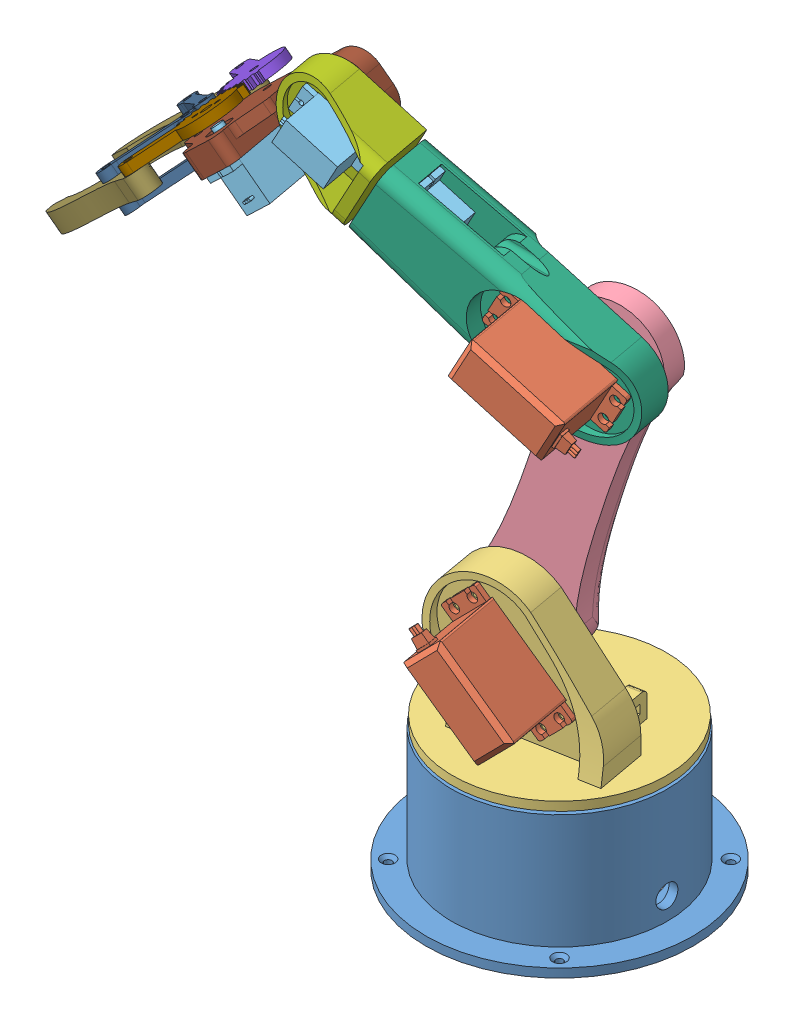
SolidWorks assembly Robotic Arm, configuration Default. Lengths in mm.
Overall size (257.43 292.37 143.8).
21 component instances, 12 part files, 26 mates.
Components (placement in the parent):
- Base-1: Base [Default] at (40.7793 36.1076 92.8796) size (121.25 56 121.25)
- Servo Motor MG996R-1: Servo Motor MG996R [Default] at (30.5293 45.3076 92.8796) x (-1 0 0) z (0 0 -1) size (55.8 47.4 21)
- Waist-1: Waist [Default] at (40.7793 93.1076 92.8796) x (-0.178802 0 -0.983885) z (0.983885 0 -0.178802) size (97 64.78 97)
- Servo Motor MG996R-2: Servo Motor MG996R [Default] at (43.1871 126.313 142.4478) x (0.695712 -0.707107 -0.126432) z (0.695712 0.707107 -0.126432) size (55.8 47.4 21)
- Arm 01-1: Arm 01 [Default] at (27.5808 133.5608 97.1076) x (-0.941109 0.291655 0.171029) z (-0.178802 0 -0.983885) size (54.87 166.68 26.36)
- Servo Motor Micro  9g-1: Servo Motor Micro  9g [Default] at (9.904 276.4834 111.1953) x (0.448013 0.890312 -0.081418) z (0.178802 0 0.983885) size (32.6 29.9 12.4)
- Servo Motor MG996R-7: Servo Motor MG996R [Default] at (61.512 253.011 139.1176) x (-0.875965 0.455351 0.15919) z (-0.448013 -0.890312 0.081418) size (55.8 47.4 21)
- Arm 02 v3-1: Arm 02 v3 [Default] at (32.6174 264.3897 101.4775) x (0.448013 0.890312 -0.081418) z (0.178802 0 0.983885) size (38.57 115 28.32)
- Arm 03-1: Arm 03 [Default] at (-16.3245 290.0092 116.0058) x (0.449545 0.890278 -0.072895) z (0.174916 -0.00771 0.984553) size (33 46 28)
- Servo Motor Micro  9g-2: Servo Motor Micro  9g [Default] at (-33.8391 300.3245 133.9765) x (0.875965 -0.455351 -0.15919) z (0.449545 0.890278 -0.072895) size (32.6 29.9 12.4)
- Gripper Assembly-1: Gripper Assembly [Default] at (-33.1508 318.0568 111.777) x (0.174916 -0.00771 0.984553) z (-0.719312 -0.683812 0.122438) size (98.22 36.05 139.41)
  - gear1-1: gear1 [Default] at (-22.9056 12.6028 63.2843) x (-0.581668 0 0.813426) z (-0.813426 0 -0.581668) size (49.29 4 26.63)
  - gear2-1: gear2 [Default] at (5.149 12.6028 46.1292) x (-0.467421 0 -0.884035) z (0.884035 0 -0.467421) size (49.02 4 26.63)
  - grip link 1-1: grip link 1 [Default] at (-26.7426 0.1028 100.5029) x (0.571471 0 -0.820623) z (0.820623 0 0.571471) size (39 4 8)
  - Gripper base-1: Gripper base [Default] at (-22.027 4.1028 80.0636) size (44.4 28 77)
  - grip link 1-2: grip link 1 [Default] at (18.9346 0.1028 100.3298) x (-0.579406 0 -0.815039) z (0.815039 0 -0.579406) size (39 4 8)
  - Gripper 1-1: Gripper 1 [Default] at (25.0683 4.1028 73.5645) x (0 1 0) z (0.39713 0 -0.917762) size (8.5 22.22 65.31)
  - Gripper 1-2: Gripper 1 [Default] at (-32.1279 12.6028 73.5771) x (0 -1 0) z (-0.371396 0 -0.928475) size (8.5 22.22 65.31)
  - Servo Motor Micro  9g-1: Servo Motor Micro  9g [Default] at (4.773 -19.4472 55.0636) x (-1 0 0) z (0 0 -1) size (32.6 29.9 12.4)
  - grip link 1-3: grip link 1 [Default] at (18.9346 12.6028 100.3298) x (-0.579406 0 -0.815039) z (0.815039 0 -0.579406) size (39 4 8)
  - grip link 1-4: grip link 1 [Default] at (-26.7426 16.6028 100.5029) x (0.571471 0 -0.820623) z (-0.820623 0 -0.571471) size (39 4 8)
Mates (geometry in assembly coordinates):
- Coincident1: coincident anti-aligned: plane of Base-1 through (40.7793 74.1076 105.8796) normal (0 1 0); plane of Servo Motor MG996R-1 through (57.8293 74.1076 102.1296) normal (0 -1 0)
- Concentric1: concentric aligned: cylinder of Base-1 through (54.5293 66.9076 87.8796) axis (0 1 0) radius 1.3; cylinder of Servo Motor MG996R-1 through (54.5293 69.7076 87.8796) axis (0 1 0) radius 2.1
- Concentric4: concentric aligned: cylinder of Base-1 through (6.5293 66.9076 97.8796) axis (0 1 0) radius 1.3; cylinder of Servo Motor MG996R-1 through (6.5293 69.7076 97.8796) axis (0 1 0) radius 2.1
- Concentric5: concentric aligned: cylinder of Base-1 through (40.7793 92.1076 92.8796) axis (0 -1 0) radius 49; cylinder of Waist-1 through (40.7793 97.1076 92.8796) axis (0 -1 0) radius 48.5
- Distance1: distance = 1 mm anti-aligned: plane of Base-1 through (40.7793 92.1076 92.8796) normal (0 1 0); plane of Waist-1 through (40.7793 93.1076 92.8796) normal (0 -1 0)
- Coincident4: coincident anti-aligned: plane of Waist-1 through (43.9977 93.1076 110.5895) normal (0.178802 0 0.983885); plane of Servo Motor MG996R-2 through (12.1802 139.0763 116.3717) normal (-0.178802 0 -0.983885)
- Coincident5: coincident anti-aligned: plane of Waist-1 through (64.4552 119.0651 137.8723) normal (-0.695712 0.707107 0.126432); plane of Servo Motor MG996R-2 through (57.9645 119.0651 102.1563) normal (0.695712 -0.707107 -0.126432)
- Coincident6: coincident anti-aligned: plane of Waist-1 through (64.4552 119.0651 137.8723) normal (-0.695712 -0.707107 0.126432); plane of Servo Motor MG996R-2 through (29.4404 148.0565 107.34) normal (0.695712 0.707107 -0.126432)
- Coincident7: coincident anti-aligned: plane of Servo Motor MG996R-2 through (27.5808 133.5608 97.1076) normal (-0.178802 0 -0.983885); plane of Arm 01-1 through (27.5808 133.5608 97.1076) normal (0.178802 0 0.983885)
- Concentric8: concentric aligned: cylinder of Servo Motor MG996R-2 through (27.5808 133.5608 97.1076) axis (0.178802 0 0.983885) radius 10.5; cylinder of Arm 01-1 through (26.6868 133.5608 92.1882) axis (0.178802 0 0.983885) radius 21
- Coincident25: coincident anti-aligned: plane of Servo Motor MG996R-7 through (36.1636 273.6775 112.0132) normal (-0.178802 0 -0.983885); plane of Arm 02 v3-1 through (34.5842 264.3897 112.3002) normal (0.178802 0 0.983885)
- Coincident26: coincident anti-aligned: plane of Servo Motor MG996R-7 through (68.2614 234.5506 100.285) normal (-0.448013 -0.890312 0.081418); plane of Arm 02 v3-1 through (69.2985 234.5506 105.9916) normal (0.448013 0.890312 -0.081418)
- Coincident27: coincident anti-aligned: plane of Servo Motor MG996R-7 through (32.3469 253.22 106.8118) normal (-0.875965 0.455351 0.15919); plane of Arm 02 v3-1 through (33.3839 253.22 112.5183) normal (0.875965 -0.455351 -0.15919)
- Concentric13: concentric anti-aligned: cylinder of Arm 01-1 through (62.0156 248.3437 90.8508) axis (-0.178802 0 -0.983885) radius 3.75; cylinder of Servo Motor MG996R-7 through (62.0154 248.3437 90.8498) axis (0.178802 0 0.983885) radius 10.5
- Coincident28: coincident anti-aligned: plane of Arm 01-1 through (27.5808 133.5608 97.1076) normal (0.178802 0 0.983885); plane of Servo Motor MG996R-7 through (62.0154 248.3437 90.8498) normal (-0.178802 0 -0.983885)
- Concentric14: concentric anti-aligned: cylinder of Servo Motor Micro  9g-1 through (-18.5722 285.5578 116.3703) axis (0.875965 -0.455351 -0.15919) radius 2.5; cylinder of Arm 02 v3-1 through (-15.1998 283.8047 115.7574) axis (-0.875965 0.455351 0.15919) radius 6.5
- Coincident30: coincident anti-aligned: plane of Servo Motor Micro  9g-1 through (2.504 299.2145 118.8416) normal (-0.875965 0.455351 0.15919); plane of Arm 02 v3-1 through (-13.1676 267.9646 121.9946) normal (0.875965 -0.455351 -0.15919)
- Parallel3: parallel anti-aligned: plane of Servo Motor Micro  9g-1 through (-15.8012 276.5772 109.5652) normal (-0.178802 0 -0.983885); plane of Arm 02 v3-1 through (-15.4921 267.9646 109.2041) normal (0.178802 0 0.983885)
- Concentric15: concentric aligned: cylinder of Servo Motor Micro  9g-1 through (-18.5722 285.5578 116.3703) axis (0.875965 -0.455351 -0.15919) radius 2.5; cylinder of Arm 03-1 through (-29.1461 291.0543 118.2919) axis (0.875965 -0.455351 -0.15919) radius 2.5
- Coincident31: coincident anti-aligned: plane of Servo Motor Micro  9g-1 through (-18.5722 285.5578 116.3703) normal (-0.875965 0.455351 0.15919); plane of Arm 03-1 through (-16.3245 290.0092 116.0058) normal (0.875965 -0.455351 -0.15919)
- Concentric16: concentric aligned: cylinder of Arm 03-1 through (-43.3003 302.8669 106.6794) axis (0.174916 -0.00771 0.984553) radius 6.5; cylinder of Servo Motor Micro  9g-2 through (-43.5365 302.8773 105.3502) axis (0.174916 -0.00771 0.984553) radius 2.5
- Parallel6: parallel anti-aligned: plane of Arm 03-1 through (-31.5066 289.5553 106.0034) normal (0.449545 0.890278 -0.072895); plane of Servo Motor Micro  9g-2 through (-50.4253 300.1222 114.2718) normal (-0.449545 -0.890278 0.072895)
- Parallel9: parallel anti-aligned: plane of Arm 03-1 through (-51.6538 300.0283 109.6648) normal (0.875965 -0.455351 -0.15919); plane of Servo Motor Micro  9g-2 through (-44.8509 311.1617 113.3679) normal (-0.875965 0.455351 0.15919)
- Coincident46: coincident anti-aligned: plane of Arm 03-1 through (-24.3542 275.3466 113.7627) normal (0.174916 -0.00771 0.984553); plane of Servo Motor Micro  9g-2 through (-48.4873 313.4056 118.3482) normal (-0.174916 0.00771 -0.984553)
- Concentric19: concentric aligned: cylinder of Servo Motor Micro  9g-2 through (-43.5365 302.8773 105.3502) axis (0.174916 -0.00771 0.984553) radius 2.5; cylinder of Gripper Assembly-1/Gripper base-1 through (-45.9853 302.9853 91.5665) axis (0.174916 -0.00771 0.984553) radius 2.5
- Coincident48: coincident anti-aligned: plane of Servo Motor Micro  9g-2 through (-43.5365 302.8773 105.3502) normal (-0.174916 0.00771 -0.984553); plane of Gripper Assembly-1/Gripper base-1 through (-69.4929 297.3643 109.9185) normal (0.174916 -0.00771 0.984553)
